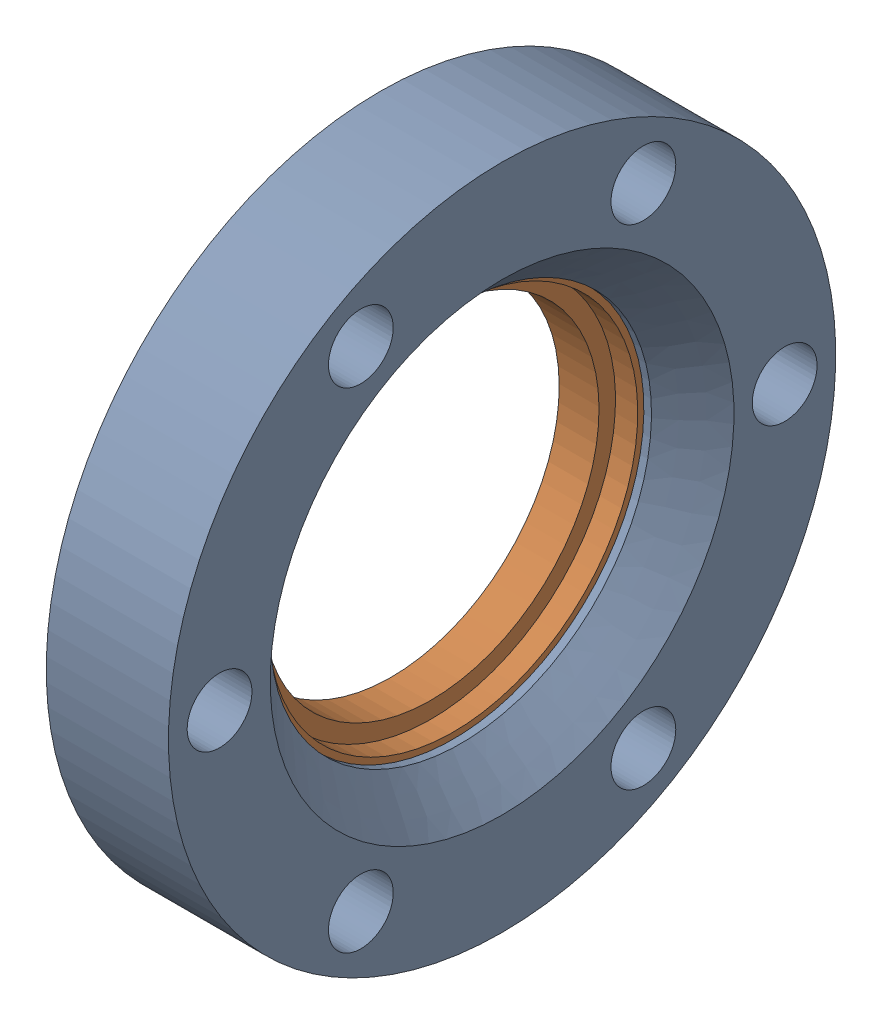
SolidWorks assembly 405002 P3_100014 (2.75 X 1.5 R)_1, configuration Default. Lengths in mm.
Overall size (12.7 69.34 69.34).
2 component instances, 2 part files, 0 mates.
Components (placement in the parent):
- 405002 P4_100014 (2.75 X 1.5 REC)_1-1: 405002 P4_100014 (2.75 X 1.5 REC)_1 [Default] at origin size (12.7 69.34 69.34)
- 405002 P5_100014 (2.75 X 1.5 INS)_1-1: 405002 P5_100014 (2.75 X 1.5 INS)_1 [Default] at (1.17 0 0) x (1 0 0) z (0 0.994423 -0.105464) size (6.96 48.1 48.1)
